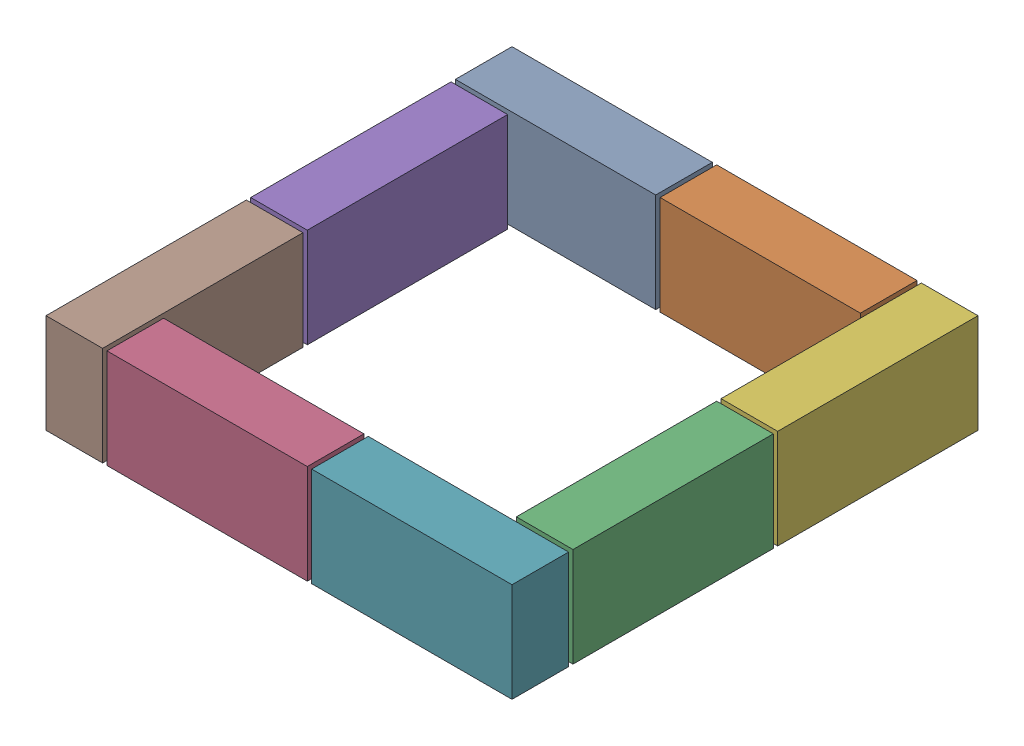
SolidWorks assembly СлойКР, configuration По умолчанию. Lengths in mm.
Overall size (535 114 535).
8 component instances, 1 part files, 6 mates.
Components (placement in the parent):
- К_огнеуп-1: К_огнеуп [По умолчанию] at (-267.5 0 -267.5) x (1 0 0) z (0 -1 0) size (230 65 114)
- К_огнеуп-2: К_огнеуп [По умолчанию] at (-32.5 0 -267.5) x (1 0 0) z (0 -1 0) size (230 65 114)
- К_огнеуп-3: К_огнеуп [По умолчанию] at (267.5 0 -32.5) x (0 0 1) z (0 -1 0) size (230 65 114)
- К_огнеуп-4: К_огнеуп [По умолчанию] at (32.5 0 267.5) x (-1 0 0) z (0 -1 0) size (230 65 114)
- К_огнеуп-5: К_огнеуп [По умолчанию] at (-267.5 0 32.5) x (0 0 -1) z (0 -1 0) size (230 65 114)
- К_огнеуп-6: К_огнеуп [По умолчанию] at (267.5 0 -267.5) x (0 0 1) z (0 -1 0) size (230 65 114)
- К_огнеуп-7: К_огнеуп [По умолчанию] at (267.5 0 267.5) x (-1 0 0) z (0 -1 0) size (230 65 114)
- К_огнеуп-8: К_огнеуп [По умолчанию] at (-267.5 0 267.5) x (0 0 -1) z (0 -1 0) size (230 65 114)
Mates (geometry in assembly coordinates):
- Совпадение1: coincident anti-aligned: plane of К_огнеуп-1 through (-267.5 0 -202.5) normal (0 -1 0)
- Совпадение4: coincident aligned: line of К_огнеуп-1 through (-267.5 0 -267.5) axis (1 0 0)
- Расстояние1: distance = 5 mm anti-aligned: plane of К_огнеуп-2 through (-32.5 0 -202.5) normal (-1 0 0); plane of К_огнеуп-1 through (-37.5 0 -202.5) normal (1 0 0)
- Совпадение6: coincident aligned: plane of К_огнеуп-1 through (-267.5 0 -267.5) normal (0 0 -1); plane of К_огнеуп-2 through (-32.5 0 -267.5) normal (0 0 -1)
- Совпадение7: coincident anti-aligned: plane of К_огнеуп-2 through (-32.5 0 -202.5) normal (0 -1 0)
- Совпадение8: coincident: plane of К_огнеуп-1 through (-267.5 0 -202.5) normal (-1 0 0)
